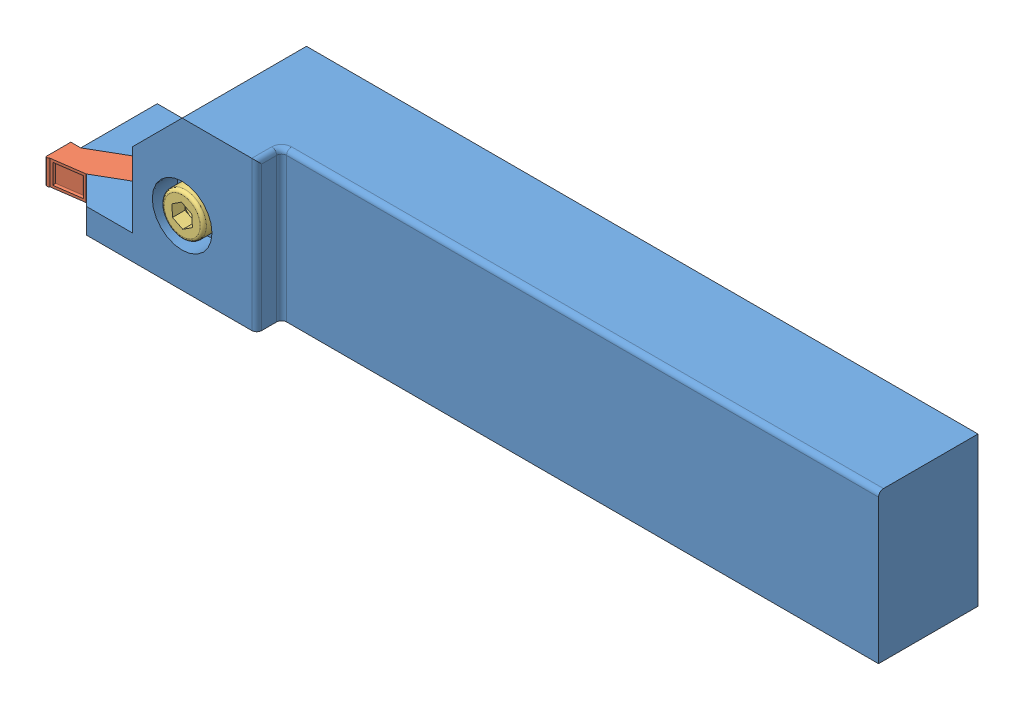
SolidWorks assembly 切断刀, configuration 默认. Lengths in mm.
Overall size (139.16 30 29.87).
3 component instances, 3 part files, 5 mates.
Components (placement in the parent):
- 切断刀刀柄-1: 切断刀刀柄 [默认] at (18.1542 12.0268 -12.5) size (135 30 25)
- 切断刀刀片-3: 切断刀刀片 [默认] at (-84.6401 2.0268 7.8462) x (0.866025 0 0.5) z (0 -1 0) size (21.49 20.95 5)
- hexagon socket head cap screws gb2-1: hexagon socket head cap screws gb2 [GB_FASTENER_SCREWS_HSHCS M5X8-N] at (-56.8458 10.0268 12.5) x (0 0 -1) z (0.056624 -0.998396 0) size (13 8.5 8.5)
Mates (geometry in assembly coordinates):
- 重合13: coincident anti-aligned: plane of 切断刀刀柄-1 through (-78.1856 17.0268 -2.1237) normal (0.5 0 0.866025); plane of 切断刀刀片-3 through (-75.3848 -2.9732 -3.7407) normal (-0.5 0 -0.866025)
- 重合14: coincident aligned: plane of 切断刀刀柄-1 through (-41.8458 -2.9732 7.5) normal (0 -1 0); plane of 切断刀刀片-3 through (-88.5444 -2.9732 7.4674) normal (0 -1 0)
- 重合16: coincident anti-aligned: line of 切断刀刀柄-1 through (-86.8458 2.0268 2.8763) axis (0 -1 0); line of 切断刀刀片-3 through (-86.8458 -2.9732 2.8763) axis (0 1 0)
- 同心1: concentric aligned: cylinder of 切断刀刀柄-1 through (-56.8458 10.0268 12.5) axis (0 0 1) radius 6; cylinder of hexagon socket head cap screws gb-1 through (-56.8458 10.0268 -0.5) axis (0 0 1) radius 2.5
- 重合17: coincident anti-aligned: plane of 切断刀刀柄-1 through (-52.8458 10.0268 7.5) normal (0 0 1); plane of hexagon socket head cap screws gb-1 through (-56.8458 10.0268 7.5) normal (0 0 -1)
